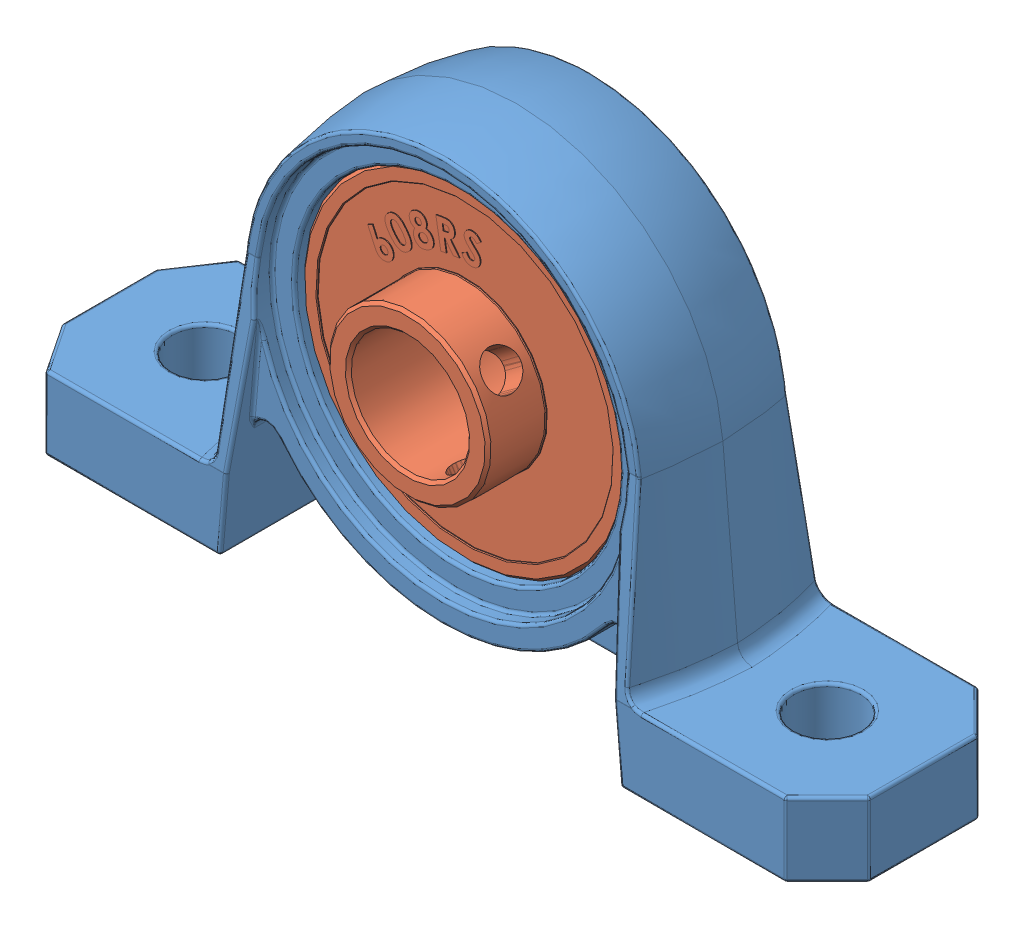
SolidWorks assembly KP08, configuration Default. Lengths in mm.
Overall size (55 40.88 13.92).
2 component instances, 2 part files, 4 mates.
Components (placement in the parent):
- KP08-2: KP08 [По умолчанию] at (2.2899 16 0) size (55 40.88 13.13)
- 608RS-2: 608RS [Default] at (2.2899 16 -3.5) x (0.16403 0.986455 0) z (0 0 1) size (22 22 10.85)
Mates (geometry in assembly coordinates):
- Концентричный2: concentric aligned: cylinder of KP08-2 through (2.2899 16 5) axis (0 0 -1) radius 11; cylinder of 608RS-2 through (2.2899 16 3.5) axis (0 0 -1) radius 11
- Расстояние1: distance = 0.5 mm aligned: plane of 608RS-2 through (2.2899 16 -3.5) normal (0 0 -1); plane of KP08-2 through (2.2899 16 -4) normal (0 0 -1)
- Совпадение2: coincident aligned: circle of KP08-2
- Совпадение3: coincident anti-aligned: plane of KP08-2 through (2.2899 0 6.5) normal (0 -1 0)
